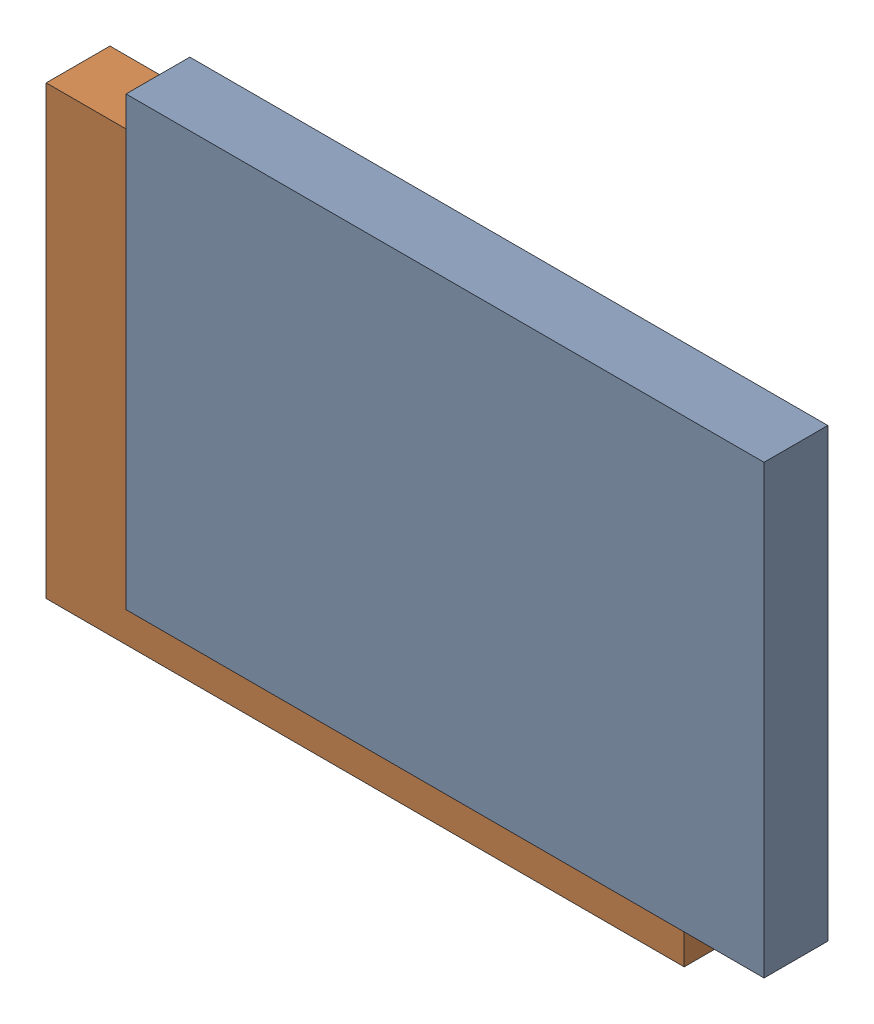
SolidWorks assembly alpha_board_enclosure, configuration Default. Lengths in mm.
Overall size (147.23 109.47 44.71).
2 component instances, 2 part files, 0 mates.
Components (placement in the parent):
- alpha_board_enclosure_bottom-1: alpha_board_enclosure_bottom [Default] at (-63.0406 -41.4214 6.244) size (100 70 10)
- alpha_board_enclosure_top-1: alpha_board_enclosure_top [Default] at (-110.2736 -80.8879 -28.4705) size (100 70 10)
